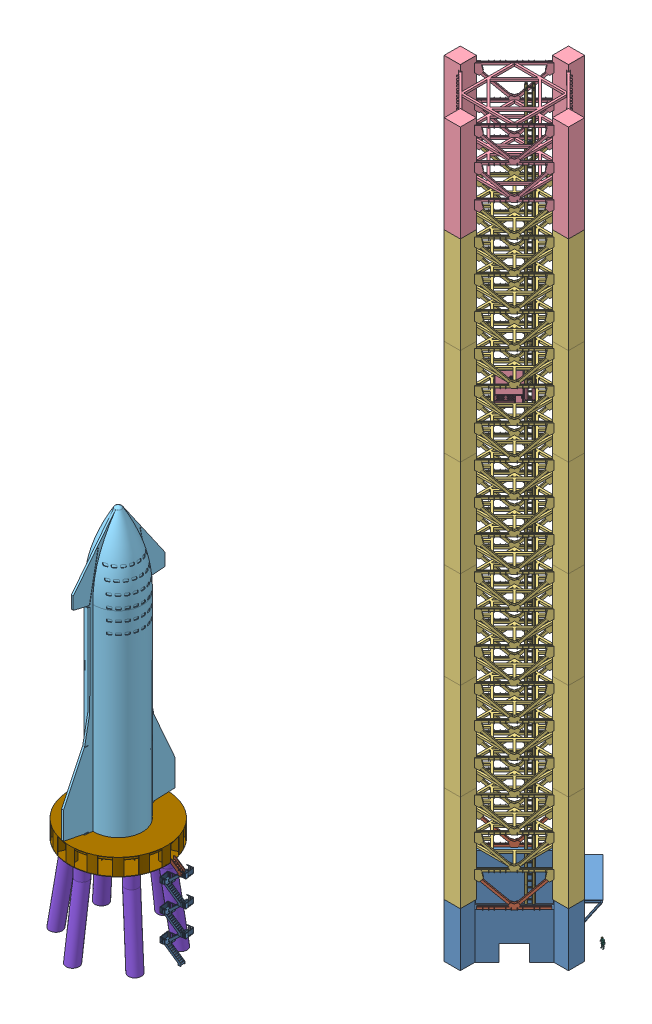
SolidWorks assembly tower assy, configuration Default. Lengths in mm.
Overall size (59605.64 136162.93 62605.51).
49 component instances, 14 part files, 73 mates.
Components (placement in the parent):
- Tower Base-1: Tower Base [Default] at (18502.1785 -15224.4561 4006.9521) x (0.707107 0 -0.707107) z (0.707107 0 0.707107) size (20897.75 10000 18485.28)
- Horizontal Rail-3: Horizontal Rail [Default] at (23382.6978 -6524.4561 8914.6579) x (0.707107 0 -0.707107) z (0.707107 0 0.707107) size (10000 5317.92 750)
- Horizontal Rail-5: Horizontal Rail [Default] at (13608.066 -6524.4561 -887.1605) x (-0.707107 0 0.707107) z (-0.707107 0 -0.707107) size (10000 5317.92 750)
- Horizontal Rail-18: Horizontal Rail [Default] at (13585.3394 -6524.4561 8878.338) x (0.707107 0 0.707107) z (-0.707107 0 0.707107) size (10000 5317.92 750)
- Tower Section-1: Tower Section [Default] at (8892.117 3769.8214 3988.3242) size (23142.14 21917.92 23142.14)
- Tower Section-2: Tower Section [Default] at (8892.117 21769.8214 3988.3242) size (23142.14 21917.92 23142.14)
- Tower Section-3: Tower Section [Default] at (8892.117 39769.8214 3988.3242) size (23142.14 21917.92 23142.14)
- Tower Section-4: Tower Section [Default] at (8892.117 57769.8214 3988.3242) size (23142.14 21917.92 23142.14)
- Tower Section-5: Tower Section [Default] at (8892.117 75769.8214 3988.3242) size (23142.14 21917.92 23142.14)
- Tower Section-6: Tower Section [Default] at (8892.117 93769.8214 3988.3242) size (23142.14 21917.92 23142.14)
- Tower Stucture Top-1: Tower Stucture Top [Default] at (8892.117 111769.8214 3988.3242) size (23142.14 18050 23142.14)
- Starship-1: Starship [Default] at (-17326.524 54344.7403 41941.9998) x (0.995646 0 0.093211) z (-0.093211 0 0.995646) size (9016.88 50472.5 19029.43)
- _WORKER-1: _WORKER [ﾃﾞﾌｫﾙﾄ] at (29647.8989 -15224.0173 -1244.0334) size (1029.59 2054.37 1938.55)
  - BODY-1: BODY [ﾃﾞﾌｫﾙﾄ] x (1 0 0) z (0 1 0) size (1029.59 357.95 1860.59)
  - HELMET-1: HELMET [ﾃﾞﾌｫﾙﾄ] at (0 1760 35) x (0 -1 0) z (1 0 0) size (140.04 282.55 225.3)
- _WORKER-2: _WORKER [ﾃﾞﾌｫﾙﾄ] at (-10832.0342 834.5981 40262.6605) x (0.999775 0.012483 0.017143) z (-0.018468 0.115225 0.993168) size (1029.59 2054.37 1938.55)
  - BODY-1: BODY [ﾃﾞﾌｫﾙﾄ] x (1 0 0) z (0 1 0) size (1029.59 357.95 1860.59)
  - HELMET-1: HELMET [ﾃﾞﾌｫﾙﾄ] at (0 1760 35) x (0 -1 0) z (1 0 0) size (140.04 282.55 225.3)
- Launch Table-1: Launch Table [Default] at (-17326.524 -15224.4561 41941.9998) size (17122.44 16000 19400.01)
- Orbital Launch Disc-1: Orbital Launch Disc [Default] at (-17326.524 775.5439 41941.9998) size (18000 3150 18000)
- Horizontal Rail-19: Horizontal Rail [Default] at (23396.0083 -6524.4561 -887.4433) x (-0.707107 0 -0.707107) z (0.707107 0 -0.707107) size (10000 5317.92 750)
- Stairs ASSY-1: Stairs ASSY [Default] at (-8446.5288 -13933.3395 40725.4833) x (-0.137165 0 -0.990548) z (0.990548 0 -0.137165) size (1730 16701.93 4317.68)
  - Stairs-1: Stairs [Default] at (-414.0766 -1291.1166 -7739.3822) size (1710 3327.63 3502.68)
  - Stairs-3: Stairs [Default] at (1225.9234 1126.5117 8564.4095) x (-1 0 0) z (0 0 -1) size (1710 3327.63 3502.68)
  - Stairs-4: Stairs [Default] at (-414.0766 3544.14 -7739.3822) size (1710 3327.63 3502.68)
  - Stairs-5: Stairs [Default] at (-414.0766 8379.3966 -7739.3822) size (1710 3327.63 3502.68)
  - Stairs-6: Stairs [Default] at (1225.9234 5961.7683 8564.4095) x (-1 0 0) z (0 0 -1) size (1710 3327.63 3502.68)
  - Stairs-7: Stairs [Default] at (1225.9234 10797.0249 8564.4095) x (-1 0 0) z (0 0 -1) size (1710 3327.63 3502.68)
  - Small Stairs-1: Small Stairs [Default] at (385.9234 13214.6532 1756.3548) x (-1 0 0) z (0 0 -1) size (910 2196.16 1960.05)
- Temp Lift Column-1: Temp Lift Column [Default] at (19972.5744 -7224.4561 2574.907) x (0.707074 0 0.70714) z (-0.70714 0 0.707074) size (1900 8150 1400)
- Temp Lift Column-2: Temp Lift Column [Default] at (19972.5744 775.5439 2574.907) x (0.707074 0 0.70714) z (-0.70714 0 0.707074) size (1900 8150 1400)
- Temp Lift Column-3: Temp Lift Column [Default] at (19972.5744 16775.5439 2574.907) x (0.707074 0 0.70714) z (-0.70714 0 0.707074) size (1900 8150 1400)
- Temp Lift Column-4: Temp Lift Column [Default] at (19972.5744 8775.5439 2574.907) x (0.707074 0 0.70714) z (-0.70714 0 0.707074) size (1900 8150 1400)
- Temp Lift Column-5: Temp Lift Column [Default] at (19972.5744 -15224.4561 2574.907) x (0.707074 0 0.70714) z (-0.70714 0 0.707074) size (1900 8150 1400)
- Temp Lift Column-6: Temp Lift Column [Default] at (19972.5744 24775.5439 2574.907) x (0.707074 0 0.70714) z (-0.70714 0 0.707074) size (1900 8150 1400)
- Temp Lift Column-7: Temp Lift Column [Default] at (19972.5744 32775.5439 2574.907) x (0.707074 0 0.70714) z (-0.70714 0 0.707074) size (1900 8150 1400)
- Temp Lift-1: Temp Lift [Default] at (19972.5744 70967.1065 2574.907) x (0.707074 0 0.70714) z (-0.70714 0 0.707074) size (5547.29 2900 5603.26)
- Pully Lift-1: Pully Lift [Default] at (19795.5751 111825.0896 2397.8911) x (-0.707074 0 -0.70714) z (0.10651 -0.988592 -0.1065) size (500.33 500 500)
- Temp Lift Column-8: Temp Lift Column [Default] at (19972.5744 40775.5439 2574.907) x (0.707074 0 0.70714) z (-0.70714 0 0.707074) size (1900 8150 1400)
- Temp Lift Column-9: Temp Lift Column [Default] at (19972.5744 56775.5439 2574.907) x (0.707074 0 0.70714) z (-0.70714 0 0.707074) size (1900 8150 1400)
- Temp Lift Column-10: Temp Lift Column [Default] at (19972.5744 48775.5439 2574.907) x (0.707074 0 0.70714) z (-0.70714 0 0.707074) size (1900 8150 1400)
- Temp Lift Column-11: Temp Lift Column [Default] at (19972.5744 64775.5439 2574.907) x (0.707074 0 0.70714) z (-0.70714 0 0.707074) size (1900 8150 1400)
- Temp Lift Column-12: Temp Lift Column [Default] at (19972.5744 72775.5439 2574.907) x (0.707074 0 0.70714) z (-0.70714 0 0.707074) size (1900 8150 1400)
- Temp Lift Column-13: Temp Lift Column [Default] at (19972.5744 80775.5439 2574.907) x (0.707074 0 0.70714) z (-0.70714 0 0.707074) size (1900 8150 1400)
- Temp Lift Column-14: Temp Lift Column [Default] at (19972.5744 88775.5439 2574.907) x (0.707074 0 0.70714) z (-0.70714 0 0.707074) size (1900 8150 1400)
- Temp Lift Column-15: Temp Lift Column [Default] at (19972.5744 96775.5439 2574.907) x (0.707074 0 0.70714) z (-0.70714 0 0.707074) size (1900 8150 1400)
- Temp Lift Column-16: Temp Lift Column [Default] at (19972.5744 104775.5439 2574.907) x (0.707074 0 0.70714) z (-0.70714 0 0.707074) size (1900 8150 1400)
- Temp Lift Column-17: Temp Lift Column [Default] at (19972.5744 112775.5439 2574.907) x (0.707074 0 0.70714) z (-0.70714 0 0.707074) size (1900 8150 1400)
- Pully Lift-2: Pully Lift [Default] at (18417.3987 73567.1065 4483.4745) x (0.707074 0 0.70714) z (0.478571 -0.736194 -0.478527) size (500.33 500 500)
Mates (geometry in assembly coordinates):
- Coincident111: coincident anti-aligned: plane of Tower Base-1 through (18502.1785 -6724.4561 4006.9521) normal (0 1 0); plane of Horizontal Rail-18 through (16838.0306 -6724.4561 12696.7147) normal (0 -1 0)
- Coincident117: coincident anti-aligned: plane of Tower Base-1 through (18502.1785 -6724.4561 4006.9521) normal (0 1 0); plane of Horizontal Rail-5 through (9789.6894 -6724.4561 2365.5307) normal (0 -1 0)
- Coincident121: coincident aligned: plane of Tower Base-1 through (17002.1785 -5224.4561 4006.9521) normal (-1 0 0); plane of Tower Section-1 through (17002.1785 -5224.4561 -4564.1158) normal (-1 0 0)
- Coincident122: coincident aligned: plane of Tower Base-1 through (18502.1785 -5224.4561 -7564.1158) normal (0 0 -1); plane of Tower Section-1 through (20002.1785 -5224.4561 -7564.1158) normal (0 0 -1)
- Coincident123: coincident aligned: plane of Tower Section-1 through (30073.2464 -5224.4561 5506.9521) normal (1 0 0); plane of Tower Section-2 through (30073.2464 12775.5439 5506.9521) normal (1 0 0)
- Coincident124: coincident aligned: plane of Tower Section-1 through (27073.2464 -5224.4561 2506.9521) normal (0 0 -1); plane of Tower Section-2 through (27073.2464 12775.5439 2506.9521) normal (0 0 -1)
- Coincident125: coincident aligned: plane of Tower Section-2 through (30073.2464 12775.5439 5506.9521) normal (1 0 0); plane of Tower Section-3 through (30073.2464 30775.5439 5506.9521) normal (1 0 0)
- Coincident126: coincident aligned: plane of Tower Section-2 through (27073.2464 12775.5439 2506.9521) normal (0 0 -1); plane of Tower Section-3 through (27073.2464 30775.5439 2506.9521) normal (0 0 -1)
- Coincident127: coincident aligned: plane of Tower Section-3 through (30073.2464 30775.5439 5506.9521) normal (1 0 0); plane of Tower Section-4 through (30073.2464 48775.5439 5506.9521) normal (1 0 0)
- Coincident128: coincident aligned: plane of Tower Section-3 through (27073.2464 30775.5439 2506.9521) normal (0 0 -1); plane of Tower Section-4 through (27073.2464 48775.5439 2506.9521) normal (0 0 -1)
- Coincident129: coincident aligned: plane of Tower Section-4 through (30073.2464 48775.5439 5506.9521) normal (1 0 0); plane of Tower Section-5 through (30073.2464 66775.5439 5506.9521) normal (1 0 0)
- Coincident130: coincident aligned: plane of Tower Section-4 through (27073.2464 48775.5439 2506.9521) normal (0 0 -1); plane of Tower Section-5 through (27073.2464 66775.5439 2506.9521) normal (0 0 -1)
- Coincident131: coincident anti-aligned: plane of Tower Section-1 through (27073.2464 12775.5439 5506.9521) normal (0 1 0); plane of Tower Section-2 through (27073.2464 12775.5439 5506.9521) normal (0 -1 0)
- Coincident132: coincident anti-aligned: plane of Tower Section-2 through (27073.2464 30775.5439 5506.9521) normal (0 1 0); plane of Tower Section-3 through (27073.2464 30775.5439 5506.9521) normal (0 -1 0)
- Coincident133: coincident anti-aligned: plane of Tower Section-3 through (27073.2464 48775.5439 5506.9521) normal (0 1 0); plane of Tower Section-4 through (27073.2464 48775.5439 5506.9521) normal (0 -1 0)
- Coincident134: coincident anti-aligned: plane of Tower Section-4 through (27073.2464 66775.5439 5506.9521) normal (0 1 0); plane of Tower Section-5 through (27073.2464 66775.5439 5506.9521) normal (0 -1 0)
- Coincident135: coincident aligned: plane of Tower Section-5 through (30073.2464 66775.5439 5506.9521) normal (1 0 0); plane of Tower Section-6 through (30073.2464 84775.5439 5506.9521) normal (1 0 0)
- Coincident136: coincident aligned: plane of Tower Section-5 through (27073.2464 66775.5439 2506.9521) normal (0 0 -1); plane of Tower Section-6 through (27073.2464 84775.5439 2506.9521) normal (0 0 -1)
- Coincident137: coincident anti-aligned: plane of Tower Section-5 through (27073.2464 84775.5439 5506.9521) normal (0 1 0); plane of Tower Section-6 through (27073.2464 84775.5439 5506.9521) normal (0 -1 0)
- Coincident138: coincident aligned: plane of Tower Section-6 through (27073.2464 84775.5439 2506.9521) normal (0 0 -1); plane of Tower Stucture Top-1 through (27073.2464 102775.5439 2506.9521) normal (0 0 -1)
- Coincident139: coincident aligned: plane of Tower Section-6 through (30073.2464 84775.5439 5506.9521) normal (1 0 0); plane of Tower Stucture Top-1 through (30073.2464 102775.5439 5506.9521) normal (1 0 0)
- Coincident140: coincident anti-aligned: plane of Tower Section-6 through (27073.2464 102775.5439 5506.9521) normal (0 1 0); plane of Tower Stucture Top-1 through (27073.2464 102775.5439 5506.9521) normal (0 -1 0)
- Tangent3: tangent anti-aligned: face of Starship-1; plane of Tower Base-1 through (18502.1785 -15224.4561 4006.9521) normal (0 -1 0)
- Coincident147: coincident anti-aligned: plane of Horizontal Rail-3 through (23665.5405 -6524.4561 9197.5006) normal (0.707107 0 0.707107); plane of Tower Section-1 through (17143.5999 -5224.4561 15719.4412) normal (-0.707107 0 -0.707107)
- Coincident148: coincident anti-aligned: plane of Tower Base-1 through (18502.1785 -6724.4561 4006.9521) normal (0 1 0); plane of Horizontal Rail-3 through (27201.0744 -6724.4561 5661.9667) normal (0 -1 0)
- Coincident149: coincident aligned: plane of Tower Base-1 through (18502.1785 -15224.4561 4006.9521) normal (0 -1 0); plane of Launch Table-1 through (-17326.524 -15224.4561 33441.9998) normal (0 -1 0)
- Concentric1: concentric aligned: circle of Launch Table-1; circle of Orbital Launch Disc-1
- Concentric2: concentric aligned: circle of Starship-1; circle of Orbital Launch Disc-1
- Coincident150: coincident anti-aligned: plane of Tower Section-1 through (18643.5999 -5224.4561 -6205.5371) normal (-0.707107 0 0.707107); plane of Horizontal Rail-19 through (23678.851 -6524.4561 -1170.286) normal (0.707107 0 -0.707107)
- Coincident151: coincident anti-aligned: plane of Tower Base-1 through (18502.1785 -6724.4561 4006.9521) normal (0 1 0); plane of Horizontal Rail-19 through (20143.3171 -6724.4561 -4705.8199) normal (0 -1 0)
- Coincident152: coincident anti-aligned: plane of Launch Table-1 through (-11480.8525 775.5439 45316.9998) normal (0 1 0); plane of Orbital Launch Disc-1 through (-17326.524 775.5439 41941.9998) normal (0 -1 0)
- Coincident154: coincident aligned: plane of Launch Table-1 through (-9965.308 -15224.4561 46191.9998) normal (0 -1 0); plane of Stairs ASSY-1/Stairs-1 through (-7142.5088 -15224.4561 40983.1297) normal (0 -1 0)
- Coincident155: coincident anti-aligned: plane of Temp Lift Column-1 through (20149.3099 -7224.4561 3458.7987) normal (0 -1 0); plane of Temp Lift Column-5 through (20149.3099 -7224.4561 3458.7987) normal (0 1 0)
- Coincident156: coincident aligned: plane of Tower Base-1 through (18502.1785 -15224.4561 4006.9521) normal (0 -1 0); plane of Temp Lift Column-5 through (20149.3099 -15224.4561 3458.7987) normal (0 -1 0)
- Tangent4: tangent anti-aligned: plane of Tower Section-1 through (20448.2389 -224.4561 2060.6202) normal (-0.70714 0 0.707074); cylinder of Temp Lift Column-1 through (20856.4496 775.5439 2751.7249) axis (0 -1 0) radius 200
- Tangent5: tangent anti-aligned: plane of Tower Section-1 through (20448.2389 -224.4561 2060.6202) normal (-0.70714 0 0.707074); cylinder of Temp Lift Column-1 through (19795.8389 775.5439 1691.0152) axis (0 -1 0) radius 200
- Concentric9: concentric aligned: cylinder of Temp Lift Column-2 through (19795.8389 8775.5439 1691.0152) axis (0 -1 0) radius 200; cylinder of Temp Lift Column-4 through (19795.8389 16775.5439 1691.0152) axis (0 -1 0) radius 200
- Coincident157: coincident aligned: circle of Temp Lift Column-2; circle of Temp Lift Column-4
- Coincident158: coincident aligned: circle of Temp Lift Column-3; circle of Temp Lift Column-4
- Coincident159: coincident aligned: circle of Temp Lift Column-3; circle of Temp Lift Column-6
- Coincident160: coincident aligned: circle of Temp Lift Column-6; circle of Temp Lift Column-7
- Coincident161: coincident aligned: circle of Temp Lift Column-1; circle of Temp Lift Column-2
- Concentric11: concentric aligned: cylinder of Temp Lift Column-1 through (20149.3099 775.5439 3458.7987) axis (0 -1 0) radius 200; cylinder of Temp Lift Column-2 through (20149.3099 8775.5439 3458.7987) axis (0 -1 0) radius 200
- Concentric12: concentric aligned: cylinder of Temp Lift Column-3 through (20856.4496 24775.5439 2751.7249) axis (0 -1 0) radius 200; cylinder of Temp Lift Column-4 through (20856.4496 16775.5439 2751.7249) axis (0 -1 0) radius 200
- Concentric13: concentric aligned: cylinder of Temp Lift Column-3 through (20149.3099 24775.5439 3458.7987) axis (0 -1 0) radius 200; cylinder of Temp Lift Column-6 through (20149.3099 32775.5439 3458.7987) axis (0 -1 0) radius 200
- Concentric14: concentric anti-aligned: cylinder of Temp Lift Column-6 through (19088.6991 32775.5439 2398.0891) axis (0 -1 0) radius 200; cylinder of Temp Lift-1 through (19088.6991 70987.1065 2398.0891) axis (0 1 0) radius 190
- Concentric16: concentric anti-aligned: cylinder of Temp Lift-1 through (20856.4496 70987.1065 2751.7249) axis (0 1 0) radius 190; cylinder of Temp Lift Column-6 through (20856.4496 32775.5439 2751.7249) axis (0 -1 0) radius 200
- Concentric17: concentric aligned: cylinder of Temp Lift Column-6 through (20149.3099 32775.5439 3458.7987) axis (0 -1 0) radius 200; cylinder of Temp Lift Column-7 through (20149.3099 40775.5439 3458.7987) axis (0 -1 0) radius 200
- Concentric19: concentric aligned: cylinder of Temp Lift Column-1 through (19088.6991 775.5439 2398.0891) axis (0 -1 0) radius 200; cylinder of Temp Lift Column-5 through (19088.6991 -7224.4561 2398.0891) axis (0 -1 0) radius 200
- Concentric21: concentric aligned: cylinder of Temp Lift Column-1 through (20856.4496 775.5439 2751.7249) axis (0 -1 0) radius 200; cylinder of Temp Lift Column-5 through (20856.4496 -7224.4561 2751.7249) axis (0 -1 0) radius 200
- Distance2: distance = 2030 mm: plane of Tower Section-1 through (16555.3936 -224.4561 2060.4387) normal (0.707074 0 0.70714); cylinder of Temp Lift Column-1 through (19795.8389 775.5439 1691.0152) axis (0 -1 0) radius 200
- Coincident162: coincident aligned: circle of Temp Lift Column-7; circle of Temp Lift Column-8
- Coincident163: coincident aligned: circle of Temp Lift Column-7; circle of Temp Lift Column-8
- Coincident164: coincident aligned: circle of Temp Lift Column-9; circle of Temp Lift Column-10
- Coincident165: coincident aligned: circle of Temp Lift Column-9; circle of Temp Lift Column-11
- Coincident166: coincident aligned: circle of Temp Lift Column-8; circle of Temp Lift Column-10
- Coincident167: coincident aligned: circle of Temp Lift Column-8; circle of Temp Lift Column-10
- Coincident168: coincident aligned: circle of Temp Lift Column-9; circle of Temp Lift Column-10
- Coincident169: coincident aligned: circle of Temp Lift Column-9; circle of Temp Lift Column-11
- Coincident170: coincident aligned: circle of Temp Lift Column-12; circle of Temp Lift Column-13
- Coincident171: coincident aligned: circle of Temp Lift Column-13; circle of Temp Lift Column-14
- Coincident172: coincident aligned: circle of Temp Lift Column-14; circle of Temp Lift Column-15
- Coincident173: coincident aligned: circle of Temp Lift Column-15; circle of Temp Lift Column-16
- Coincident174: coincident aligned: circle of Temp Lift Column-11; circle of Temp Lift Column-12
- Coincident175: coincident aligned: circle of Temp Lift Column-16; circle of Temp Lift Column-17
- Coincident176: coincident aligned: circle of Temp Lift Column-16; circle of Temp Lift Column-17
- Coincident177: coincident aligned: circle of Temp Lift Column-15; circle of Temp Lift Column-16
- Coincident178: coincident aligned: circle of Temp Lift Column-14; circle of Temp Lift Column-15
- Coincident179: coincident aligned: circle of Temp Lift Column-13; circle of Temp Lift Column-14
- Coincident180: coincident aligned: circle of Temp Lift Column-12; circle of Temp Lift Column-13
- Coincident181: coincident aligned: circle of Temp Lift Column-11; circle of Temp Lift Column-12
- Concentric22: concentric anti-aligned: cylinder of Temp Lift-1 through (18488.1061 73567.1065 4554.1885) axis (-0.707074 0 -0.70714) radius 50; cylinder of Pully Lift-2 through (18028.5081 73567.1065 4094.5476) axis (0.707074 0 0.70714) radius 50
- Distance3: distance = 50 mm anti-aligned: plane of Pully Lift-2 through (18417.3987 73567.1065 4483.4745) normal (0.707074 0 0.70714); plane of Temp Lift-1 through (18770.9653 70967.1065 4200.6483) normal (-0.707074 0 -0.70714)
